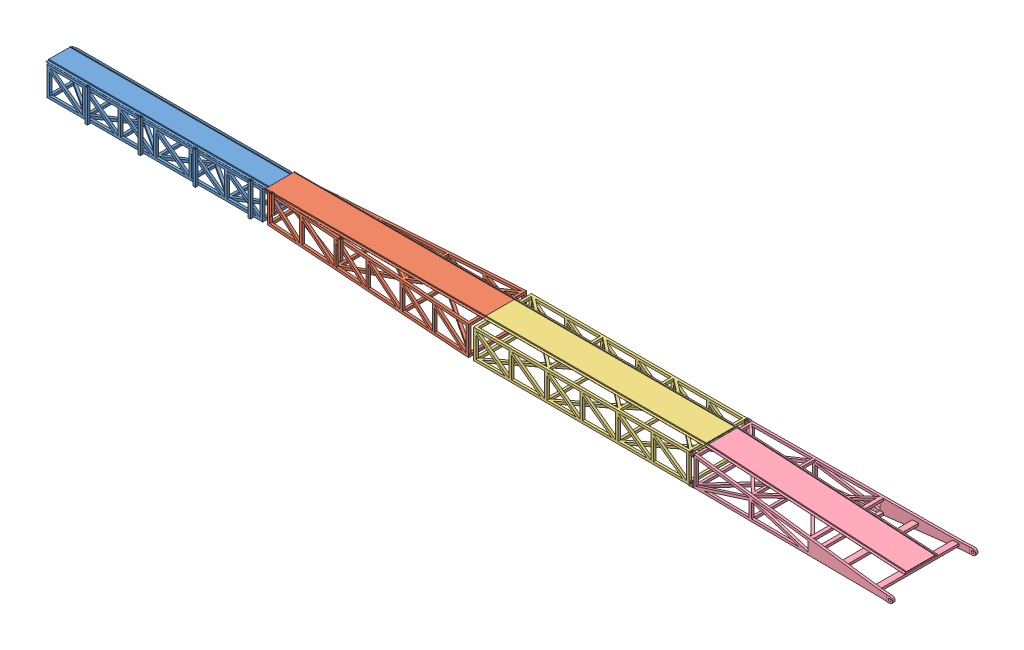
SolidWorks assembly Starboard Boom, configuration Default. Lengths in mm.
Overall size (18421.35 653.59 1793.24).
8 component instances, 8 part files, 12 mates.
Components (placement in the parent):
- End Section-1: End Section [Default] at origin size (4651.38 647.7 622.3)
- Angled Section Flush-1: Angled Section Flush [Default] at (9153.525 558.8 914.4) size (4629.15 641.35 1219.2)
- Mid Section-1: Mid Section [Default] at (9255.125 0 -304.8) size (4658.36 647.7 1231.9)
- Base Section-1: Base Section [Default] at (18281.65 304.8 304.8) x (-1 0 0) z (0 0 -1) size (4540.89 653.59 1793.24)
- PortEnd Section-3: PortEnd Section [Default] at (36563.3 0 0) x (-1 0 0) z (0 0 -1) (suppressed, hidden)
- PortAngled Section Flush-3: PortAngled Section Flush [Default] at (27409.775 558.8 914.4) x (-1 0 0) z (0 0 -1) (suppressed, hidden)
- PortMid Section-3: PortMid Section [Default] at (27308.175 0 -304.8) x (-1 0 0) z (0 0 -1) (suppressed, hidden)
- PortBase Section-3: PortBase Section [Default] at (18281.65 304.8 304.8) (suppressed, hidden)
Mates (geometry in assembly coordinates):
- Coincident1: coincident aligned: plane of End Section-1 through (0 0 0) normal (0 1 0); plane of assembly through (0 0 0) normal (0 1 0)
- Coincident2: coincident aligned: plane of End Section-1 through (0 0 0) normal (0 0 1); plane of assembly through (0 0 0) normal (0 0 1)
- Coincident3: coincident aligned: plane of End Section-1 through (0 0 0) normal (1 0 0); plane of assembly through (0 0 0) normal (1 0 0)
- Coincident4: coincident aligned: plane of Angled Section Flush-1 through (9153.525 558.8 304.8) normal (0 0 1); plane of End Section-1 through (0 0 304.8) normal (0 0 1)
- Coincident5: coincident aligned: plane of End Section-1 through (0 0 50.8) normal (0 -1 0); plane of Angled Section Flush-1 through (9153.525 0 914.4) normal (0 -1 0)
- Coincident6: coincident anti-aligned: plane of End Section-1 through (4575.175 0 50.8) normal (1 0 0); plane of Angled Section Flush-1 through (4575.175 609.6 0) normal (-1 0 0)
- Coincident7: coincident aligned: plane of Angled Section Flush-1 through (9153.525 558.8 304.8) normal (0 0 1); plane of Mid Section-1 through (9255.125 0 304.8) normal (0 0 1)
- Coincident8: coincident aligned: plane of Angled Section Flush-1 through (9153.525 0 914.4) normal (0 -1 0); plane of Mid Section-1 through (9255.125 0 -254) normal (0 -1 0)
- Coincident9: coincident anti-aligned: plane of Angled Section Flush-1 through (9204.325 631.825 603.25) normal (1 0 0); plane of Mid Section-1 through (9204.325 631.825 6.35) normal (-1 0 0)
- Coincident10: coincident aligned: plane of Mid Section-1 through (9255.125 0 -254) normal (0 -1 0); plane of Base Section-1 through (13935.075 0 -658.5681) normal (0 -1 0)
- Distance1: distance = 101.6 mm anti-aligned: plane of Base Section-1 through (13884.275 609.6 1268.1681) normal (-1 0 0); plane of Mid Section-1 through (13782.675 0 -254) normal (1 0 0)
- Coincident12: coincident anti-aligned: plane of Mid Section-1 through (9255.125 0 304.8) normal (0 0 1); plane of Base Section-1 through (18281.65 304.8 304.8) normal (0 0 -1)
